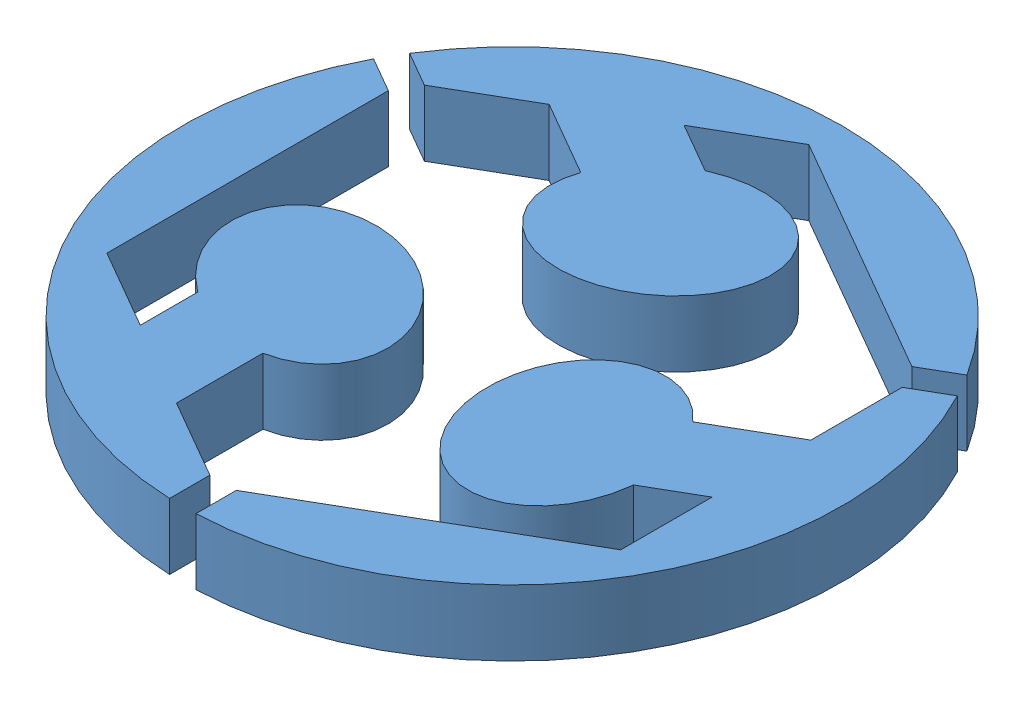
SolidWorks assembly FabLogo - Assembly, configuration Default. Lengths in mm.
Overall size (118.27 17.95 123.21).
3 component instances, 1 part files, 6 mates.
Components (placement in the parent):
- Example5-FabLogo-1: Example5-FabLogo [Default] at origin size (50 17.95 73.21)
- Example5-FabLogo-2: Example5-FabLogo [Default] x (-0.5 0 -0.866025) z (0.866025 0 -0.5) size (50 17.95 73.21)
- Example5-FabLogo-3: Example5-FabLogo [Default] x (-0.5 0 0.866025) z (-0.866025 0 -0.5) size (50 17.95 73.21)
Mates (geometry in assembly coordinates):
- Coincident3: coincident: point of Example5-FabLogo-1; point of Example5-FabLogo-2
- Coincident5: coincident: point of Example5-FabLogo-1; point of Example5-FabLogo-2
- Coincident6: coincident: point of Example5-FabLogo-3; point of Example5-FabLogo-1
- Coincident7: coincident: point of Example5-FabLogo-2; point of Example5-FabLogo-3
- Parallel1: parallel anti-aligned: plane of Example5-FabLogo-1 through (-2 10 0) normal (1 0 0); plane of Example5-FabLogo-2 through (2 10 0) normal (-1 0 0)
- Parallel2: parallel anti-aligned: plane of Example5-FabLogo-2 through (1 10 1.7321) normal (-0.5 0 -0.866025); plane of Example5-FabLogo-3 through (-1 10 -1.7321) normal (0.5 0 0.866025)
